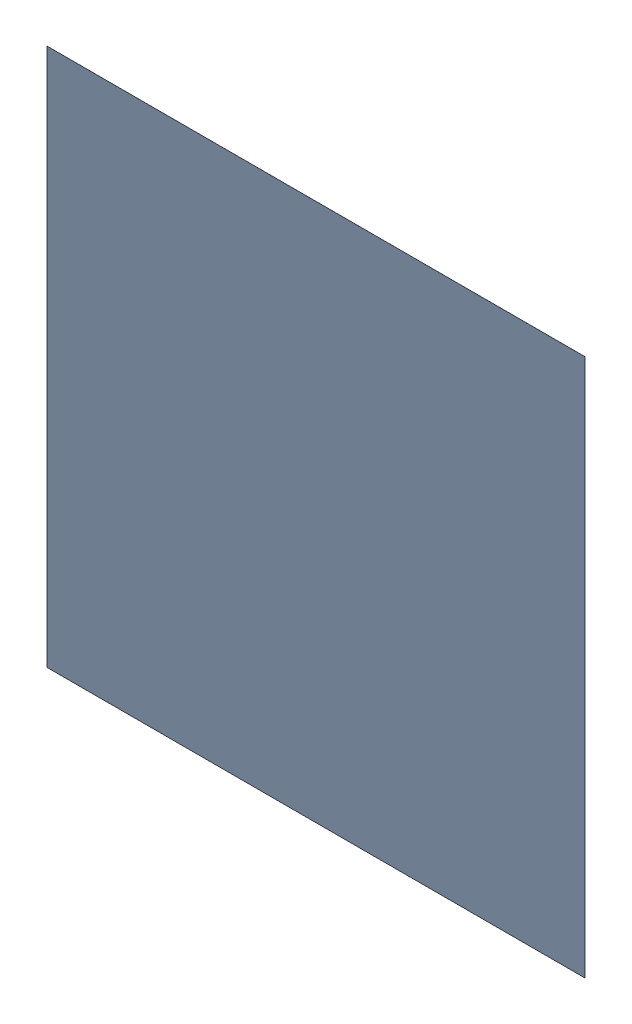
SolidWorks assembly X4, configuration Standard. Lengths in mm.
Overall size (0.05 0.05 0).
2 component instances, 1 part files, 0 mates.
Components (placement in the parent):
- 6269211456-1: 6269211456 [Standard] at (-10.3 -23.5 0) x (0 1 0) z (0 0 1) size (0.05 0.05 0)
  - Extruded-3-1: Extruded-3 [Standard] at origin size (0.05 0.05 0)
